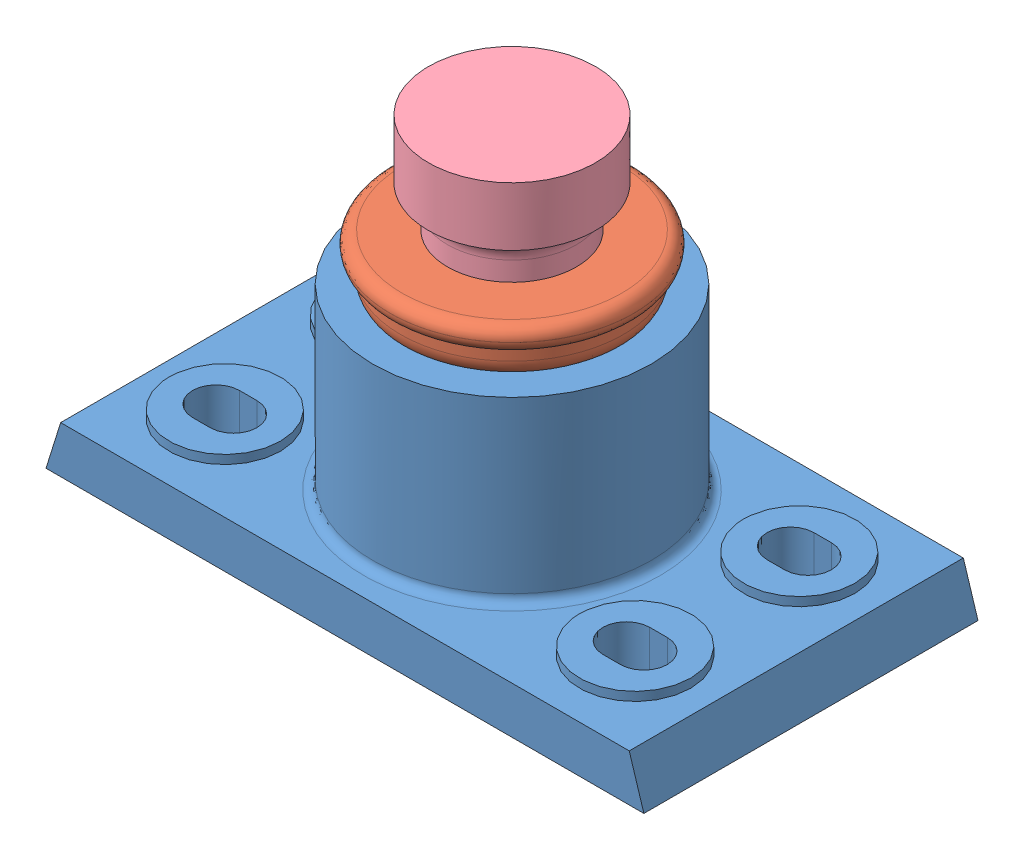
SolidWorks assembly Assem1, configuration Default. Lengths in mm.
Overall size (204 127 114).
4 component instances, 4 part files, 7 mates.
Components (placement in the parent):
- Ak Body-1: Ak Body [Default] at (89.4455 73.8601 171.7172) size (204 77 114)
- Ak Bush-1: Ak Bush [Default] at (89.4455 89.8601 171.7172) size (83 77 83)
- Ak Pad-1: Ak Pad [Default] at (89.4455 89.8601 171.7172) size (44 16 44)
- Ak Shaft-1: Ak Shaft [Default] at (89.4455 105.8601 171.7172) size (57 95 57)
Mates (geometry in assembly coordinates):
- Coincident1: coincident anti-aligned: plane of Ak Body-1 through (89.4455 89.8601 171.7172) normal (0 1 0); plane of Ak Bush-1 through (111.4455 89.8601 171.7172) normal (0 -1 0)
- Concentric2: concentric anti-aligned: cylinder of Ak Body-1 through (67.4455 89.8601 171.7172) axis (0 1 0) radius 1.5; cylinder of Ak Bush-1 through (67.4455 89.8601 171.7172) axis (0 -1 0) radius 1.5
- Coincident2: coincident anti-aligned: plane of Ak Body-1 through (89.4455 89.8601 171.7172) normal (0 1 0); plane of Ak Pad-1 through (89.4455 89.8601 171.7172) normal (0 -1 0)
- Concentric3: concentric anti-aligned: cylinder of Ak Body-1 through (67.4455 89.8601 171.7172) axis (0 1 0) radius 1.5; cylinder of Ak Pad-1 through (67.4455 94.8601 171.7172) axis (0 -1 0) radius 1.5
- Concentric4: concentric aligned: cylinder of Ak Bush-1 through (89.4455 89.8601 171.7172) axis (0 -1 0) radius 22; cylinder of Ak Shaft-1 through (89.4455 105.8601 171.7172) axis (0 -1 0) radius 22
- Concentric5: concentric aligned: cylinder of Ak Body-1 through (89.4455 73.8601 171.7172) axis (0 -1 0) radius 32.5; cylinder of Ak Bush-1 through (89.4455 89.8601 171.7172) axis (0 -1 0) radius 29.5
- Tangent1: tangent anti-aligned: sphere of Ak Pad-1; plane of Ak Shaft-1 through (89.4455 105.8601 171.7172) normal (0 -1 0)
